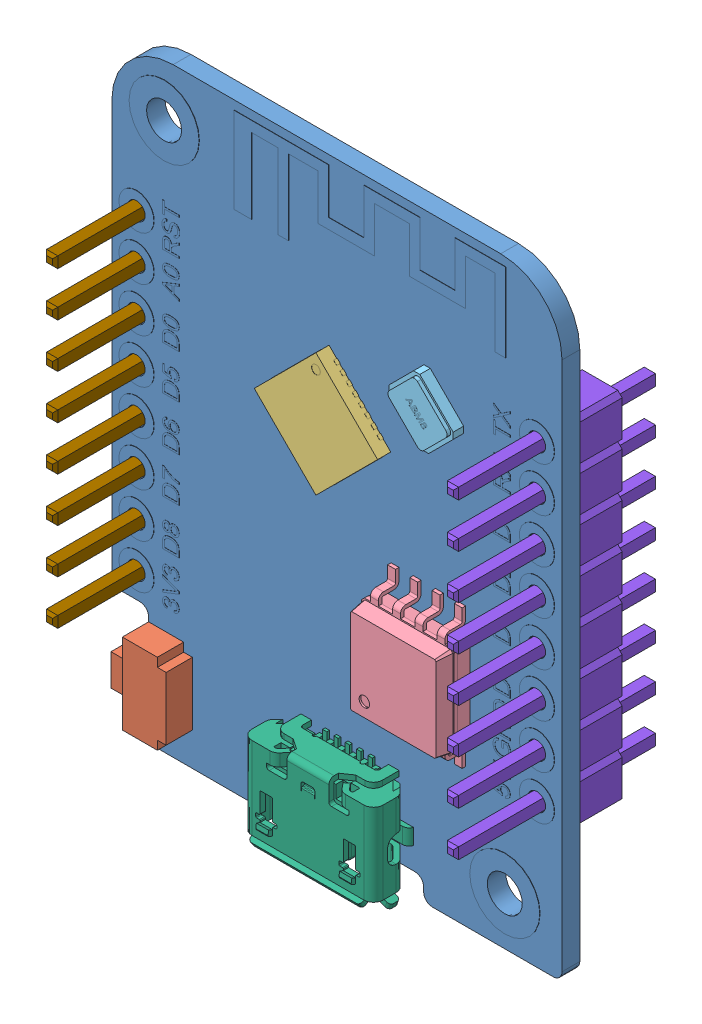
SolidWorks assembly WEMOS_D1_MINI_V3.0.0, configuration Défaut. Lengths in mm.
Overall size (25.7 34.25 11.54).
9 component instances, 9 part files, 0 mates.
Components (placement in the parent):
- WEMOS_D1_MINI_V_3_0_0_PCB_180112_01-1: WEMOS_D1_MINI_V_3_0_0_PCB_180112_01 [Défaut] at origin size (25.7 34.25 1.05)
- WEMOS_D1_MINI_V_3_0_0_PUSH_BUTTON_180111_01-1: WEMOS_D1_MINI_V_3_0_0_PUSH_BUTTON_180111_01 [Défaut] at (-9.5 -13.425 1.258) size (3.5 4.6 1.5)
- QFN_32_1EP_5x5mm_Pitch0_5mm_step1_01-1: QFN_32_1EP_5x5mm_Pitch0_5mm_step1_01 [Défaut] at (-0.4286 4.2036 0.508) x (0.707107 -0.707107 0) z (0 0 1) size (5 5 0.77)
- SOIJ_8_5_3x5_3mm_Pitch1_27mm_step1_01-1: SOIJ_8_5_3x5_3mm_Pitch1_27mm_step1_01 [Défaut] at (5.22 -5.255 0.508) x (0 1 0) z (0 0 1) size (7.94 5.3 2.01)
- ABM8_STEP1_01-1: ABM8_STEP1_01 [Défaut] at (5.4013 7.615 0.5083) x (0.707107 -0.707107 0) z (-0.707107 -0.707107 0) size (3.2 0.8 2.49)
- _050170001_stp1_01-1: _050170001_stp1_01 [Défaut] at (0.75 -13.975 1.693) x (1 0 0) z (0 -1 0) size (8.2 3.3 5.4)
- SOIC_16_3_9x9_9mm_Pitch1_27mm_step1_01-1: SOIC_16_3_9x9_9mm_Pitch1_27mm_step1_01 [Défaut] at (-2.85 -5.075 -0.508) x (-1 0 0) z (0 0 -1) size (6 9.9 1.75)
- Pin_Header_Straight_1x08_Pitch2_54mm_step1_01-1: Pin_Header_Straight_1x08_Pitch2_54mm_step1_01 [Défaut] at (11.44 8.875 -3.0658) size (2.54 20.32 11.54)
- Pin_Header_Straight_1x08_Pitch2_54mm_step1_01001-1: Pin_Header_Straight_1x08_Pitch2_54mm_step1_01001 [Défaut] at (-11.44 8.875 -3.0658) size (2.54 20.32 11.54)
